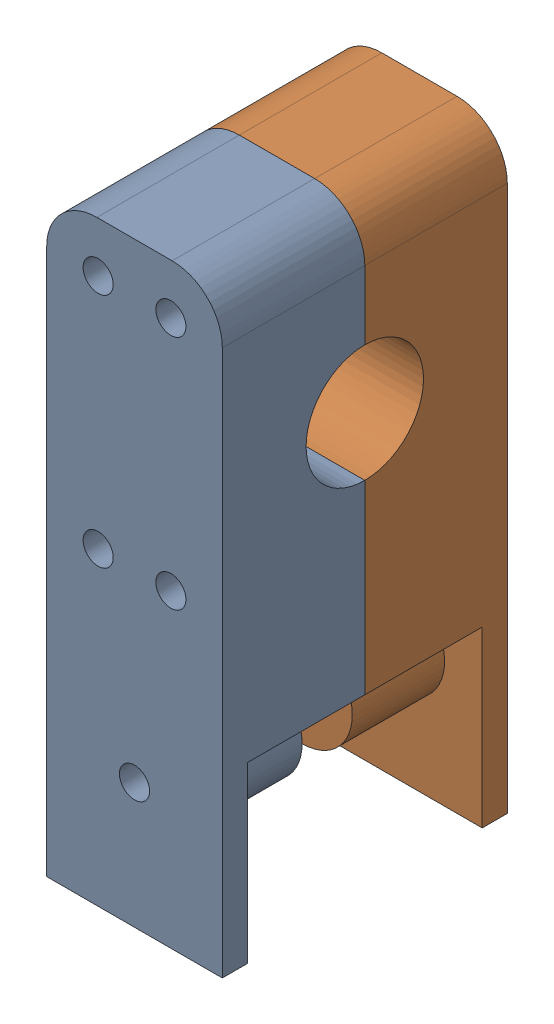
SolidWorks assembly Hangblock-assembly, configuration Default. Lengths in mm.
Overall size (35 118.8 56.8).
2 component instances, 2 part files, 4 mates.
Components (placement in the parent):
- Hangblock-001-R-1: Hangblock-001-R [Default] at origin size (35 118.8 33.4)
- Hangblock-002-L-1: Hangblock-002-L [Default] at (35 0 0) x (-1 0 0) z (0 0 -1) size (35 118.8 28.4)
Mates (geometry in assembly coordinates):
- Coincident3: coordinate: point of Hangblock-001-R-1
- Coincident4: coincident anti-aligned: plane of Hangblock-001-R-1 through (0 59.4 0) normal (0 0 -1); plane of Hangblock-002-L-1 through (35 59.4 0) normal (0 0 1)
- Concentric1: concentric anti-aligned: cylinder of Hangblock-001-R-1 through (17.5 -34.4 -28.4) axis (0 0 1) radius 3; cylinder of Hangblock-002-L-1 through (17.5 -34.4 28.4) axis (0 0 -1) radius 3
- Concentric2: concentric anti-aligned: cylinder of Hangblock-001-R-1 through (24.75 49.4 -28.4) axis (0 0 1) radius 3; cylinder of Hangblock-002-L-1 through (24.75 49.4 28.4) axis (0 0 -1) radius 3
